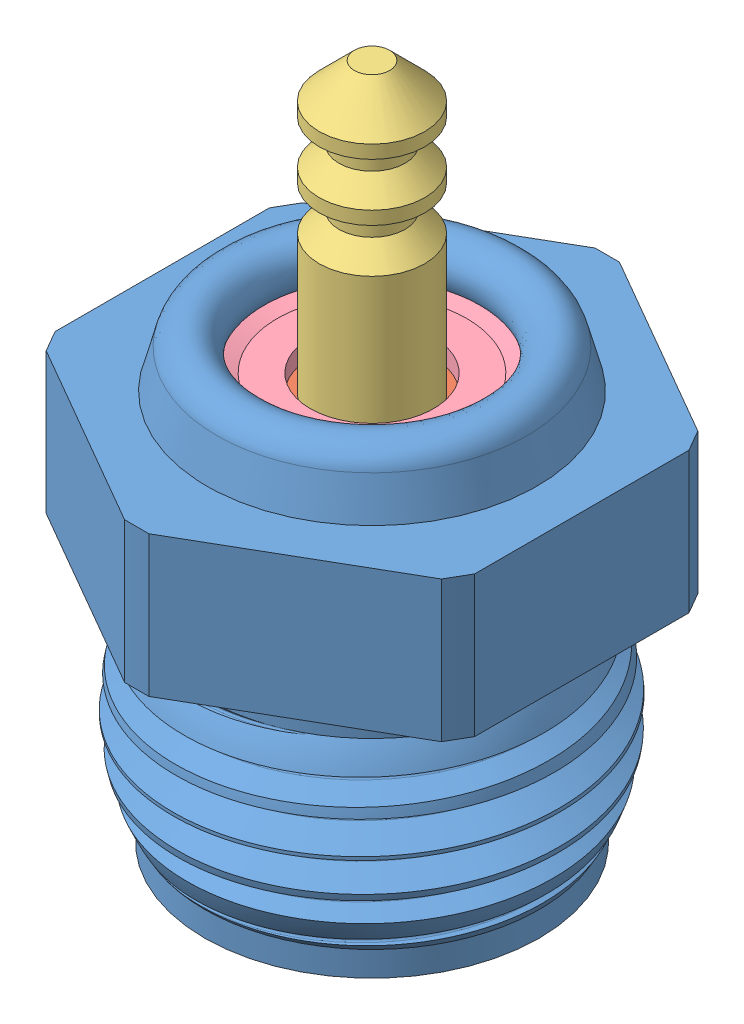
SolidWorks assembly -NelsonGlowplug, configuration Default. Lengths in mm.
Overall size (9.53 16.4 10.7).
6 component instances, 5 part files, 9 mates.
Components (placement in the parent):
- GlowplugHouse-1: GlowplugHouse [Default] at origin size (9.53 10.9 10.7)
- GlowplugIsolator-1: GlowplugIsolator [Default] at (0 3 0) size (6 0.1 6)
- GlowplugElectrode-1: GlowplugElectrode [Default] at (0 3.1 0) size (5.5 13 5.5)
- GlowplugIsolator-2: GlowplugIsolator [Default] at (0 9.45 0) size (6 0.1 6)
- GlowplugSpring-1: GlowplugSpring [Default] at (0 9.55 0) size (6 0.71 6)
- GlowplugElement-1: GlowplugElement [Default] at (0 -0.1275 0) size (1.5 3.38 2.71)
Mates (geometry in assembly coordinates):
- Coincident1: coincident anti-aligned: plane of GlowplugHouse-1 through (1.1 3 0) normal (0 1 0); plane of GlowplugIsolator-1 through (0 3 0) normal (0 -1 0)
- Concentric1: concentric anti-aligned: cylinder of GlowplugHouse-1; cylinder of GlowplugIsolator-1
- Concentric2: concentric aligned: cylinder of GlowplugHouse-1; cylinder of GlowplugElectrode-1
- Coincident2: coincident anti-aligned: plane of GlowplugIsolator-1 through (0 3.1 0) normal (0 1 0); plane of GlowplugElectrode-1 through (0 3.1 0) normal (0 -1 0)
- Concentric3: concentric anti-aligned: cylinder of GlowplugHouse-1; cylinder of GlowplugIsolator-2
- Coincident3: coincident anti-aligned: plane of GlowplugElectrode-1 through (2.75 9.45 0) normal (0 1 0); plane of GlowplugIsolator-2 through (0 9.45 0) normal (0 -1 0)
- Concentric4: concentric anti-aligned: cylinder of GlowplugHouse-1; cylinder of GlowplugSpring-1
- Coincident4: coincident anti-aligned: plane of GlowplugIsolator-2 through (0 9.55 0) normal (0 1 0); plane of GlowplugSpring-1 through (1.4 9.55 0) normal (0 -1 0)
- Concentric5: concentric aligned: cylinder of GlowplugHouse-1; line of GlowplugElement-1
